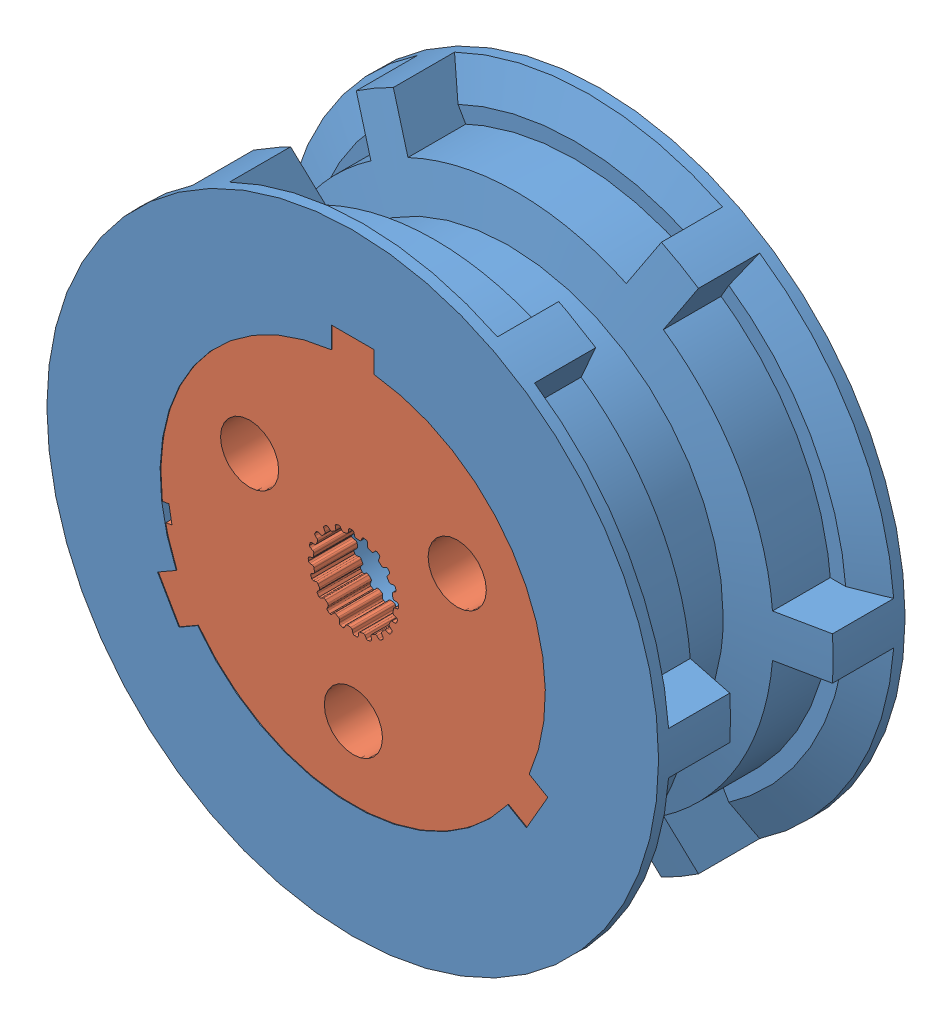
SolidWorks assembly DriveWheel, configuration Default. Lengths in mm.
Overall size (45.38 45.43 18.29).
3 component instances, 2 part files, 6 mates.
Components (placement in the parent):
- Custom Axle Drive_LEGO UWheel_6x3-1: Custom Axle Drive_LEGO UWheel_6x3 [Default] at (-5.8421 26.8291 44.8442) size (45.38 45.43 18.29)
- WheelPlates w-Custom Axle-1: WheelPlates w-Custom Axle [Default] at (-5.8421 26.8291 50.737) x (0.5 -0.866025 0) z (0 0 1) size (28.95 30.08 3.2)
- WheelPlates w-Custom Axle-2: WheelPlates w-Custom Axle [Default] at (-5.8421 26.8291 35.751) x (0.5 -0.866025 0) z (0 0 1) size (28.95 30.08 3.2)
Mates (geometry in assembly coordinates):
- Concentric1: concentric: cylinder of Custom Axle Drive_LEGO UWheel_6x3-1 through (-13.5411 31.2741 34.0662) axis (0 0 1) radius 1.7272; cylinder of WheelPlates w-Custom Axle-1 through (-13.5411 31.2741 44.6305) axis (0 0 1) radius 2.159
- Concentric2: concentric: cylinder of Custom Axle Drive_LEGO UWheel_6x3-1 through (-5.8421 17.9391 34.0662) axis (0 0 1) radius 1.7272; cylinder of WheelPlates w-Custom Axle-1 through (-5.8421 17.9391 44.6305) axis (0 0 1) radius 2.159
- Coincident1: coincident: plane of Custom Axle Drive_LEGO UWheel_6x3-1 through (-5.8421 26.8291 50.737) normal (0 0 1); plane of WheelPlates w-Custom Axle-1 through (-5.8421 26.8291 50.737) normal (0 0 -1)
- Concentric3: concentric: cylinder of Custom Axle Drive_LEGO UWheel_6x3-1 through (-13.5411 31.2741 34.0662) axis (0 0 1) radius 1.7272; cylinder of WheelPlates w-Custom Axle-2 through (-13.5411 31.2741 29.6445) axis (0 0 1) radius 2.159
- Concentric4: concentric: cylinder of Custom Axle Drive_LEGO UWheel_6x3-1 through (1.8568 31.2741 34.0662) axis (0 0 1) radius 1.7272; cylinder of WheelPlates w-Custom Axle-2 through (1.8568 31.2741 29.6445) axis (0 0 1) radius 2.159
- Coincident3: coincident: plane of Custom Axle Drive_LEGO UWheel_6x3-1 through (-5.8421 26.8291 38.9514) normal (0 0 -1); plane of WheelPlates w-Custom Axle-2 through (-5.8421 26.8291 38.9514) normal (0 0 1)
